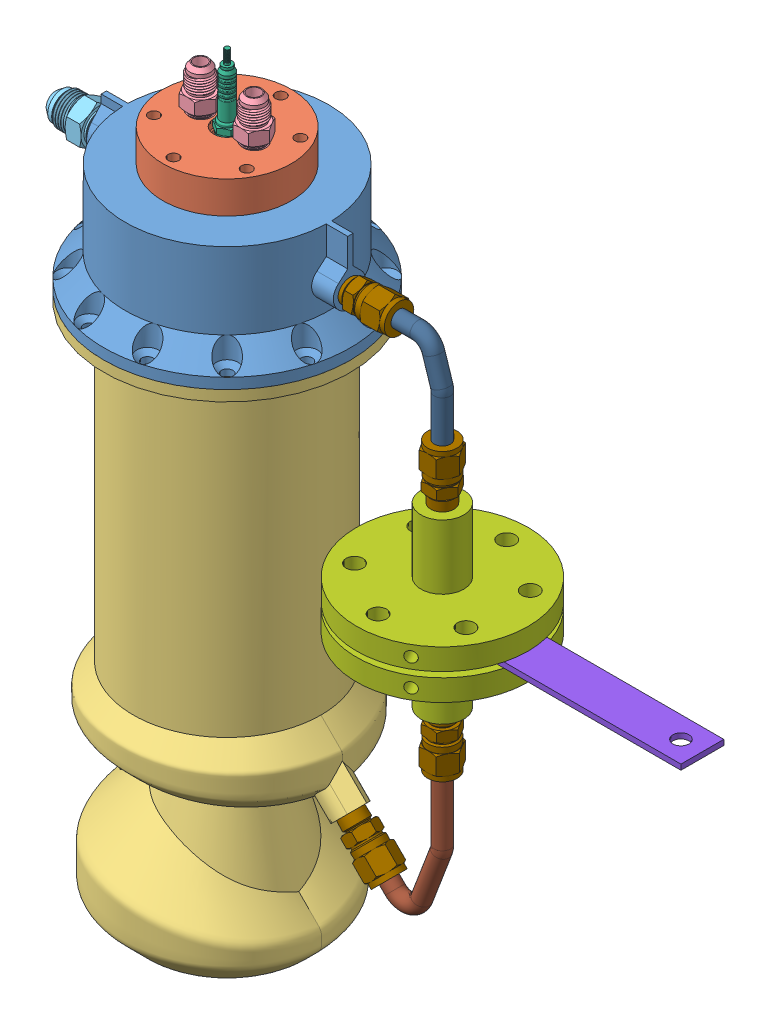
SolidWorks assembly regen additive coax swirl engine 3, configuration Default. Lengths in mm.
Overall size (382.94 487.36 146.05).
20 component instances, 11 part files, 17 mates.
Components (placement in the parent):
- addative coax swirl injector7-1: addative coax swirl injector7 [Default] at origin size (146.05 73.82 146.05)
- addative igniter 1-1: addative igniter 1 [Default] at origin size (76.2 88.9 76.2)
- slot cooling jacket 13-1: slot cooling jacket 13 [Default] at (0 5.5443 0) size (155.69 363.49 146.05)
- 5482K113_0.375AN-0.25NPT-2: 5482K113_0.375AN-0.25NPT [5482K113] at (15.875 96.9061 0) x (0 1 0) z (0 0 1) size (35.31 18.33 15.88)
- 5482K113_0.375AN-0.25NPT-3: 5482K113_0.375AN-0.25NPT [5482K113] at (-15.875 96.9061 0) x (0 1 0) z (0 0 1) size (35.31 18.33 15.88)
- 5482K114_0.5AN-0.375NPT-1: 5482K114_0.5AN-0.375NPT [5482K114] at (-82.4154 50.8 0) x (-1 0 0) z (0 0 1) size (38.48 23.83 20.64)
- 5482K114_0.5AN-0.375NPT-2: 5482K114_0.5AN-0.375NPT [5482K114] at (-66.5973 -242.1674 0) x (-0.707107 0.707107 0) z (0 0 1) size (38.48 23.83 20.64)
- SparkPlug-1: SparkPlug [Default] at (0 67.1261 0) size (15.5 63.67 13.54)
- orifice_flow_meter-1: orifice_flow_meter [Default] at (127.489 -40.2634 0) x (0 0 -1) z (1 0 0) size (138.79 104.77 223.38)
  - orifice_flow_meter_flange-1: orifice_flow_meter_flange [Default] at origin size (101.6 50.8 101.6)
  - 2206N11_Flange-Mount Flow-Control Orifice-1: 2206N11_Flange-Mount Flow-Control Orifice [2206N11] at (0 -52.3875 0) x (1 0 0) z (0 -1 0) size (53.98 180.97 3.17)
  - orifice_flow_meter_flange-2: orifice_flow_meter_flange [Default] at (0 -104.775 0) x (0.5 0 -0.866025) z (-0.866025 0 -0.5) size (101.6 50.8 101.6)
- Tube_1-regen additive coax swirl engine 3-001-1: Tube_1-regen additive coax swirl engine 3-001 [Default] at origin size (75.64 100.99 53.94)
  - straight fitting-1: straight fitting [.38 TUBE X .25 NPT] at (127.489 -47.7996 0) x (0 -1 0) z (0 0 1) size (39.88 20.16 17.46)
  - straight fitting-2: straight fitting [.38 TUBE X .25 NPT] at (61.9328 41.275 0) x (-1 0 0) z (0 0.924225 0.381849) size (39.88 20.16 17.46)
  - Tube-375X035^Tube_1-regen additive coax swirl engine 3-001-1: Tube-375X035^Tube_1-regen additive coax swirl engine 3-001 [Tube .375in OD X .035in Wall] at (127.489 -24.6856 0) x (0.707107 0 0.707107) z (0 1 0) size (38.14 38.14 70.72) (virtual)
- Tube_2-regen additive coax swirl engine 3-1: Tube_2-regen additive coax swirl engine 3 [Default] at origin size (113.38 130.09 92.49)
  - straight fitting-1: straight fitting [.38 TUBE X .25 NPT] at (67.8089 -221.0147 0) x (-0.707107 0.707107 0) z (0 0 1) size (39.88 20.16 17.46)
  - straight fitting-2: straight fitting [.38 TUBE X .25 NPT] at (127.489 -137.5023 0) x (0 1 0) z (0 0 1) size (39.88 20.16 17.46)
  - Tube-375X035^Tube_2-regen additive coax swirl engine 3-1: Tube-375X035^Tube_2-regen additive coax swirl engine 3 [Tube .375in OD X .035in Wall] at (84.153 -237.3587 0) x (0.57735 0.57735 0.57735) z (0.707107 -0.707107 0) size (77.98 58.13 63.11) (virtual)
Mates (geometry in assembly coordinates):
- Coincident1: coordinate: point of addative coax swirl injector7-1
- Coincident2: coincident aligned: cone of addative coax swirl injector7-1 through (0 26.1937 0) axis (0 -1 0); cone of addative igniter 1-1 through (0 44.45 0) axis (0 -1 0)
- Concentric2: concentric aligned: cylinder of addative coax swirl injector7-1 through (-27.4963 69.85 -15.875) axis (0 1 0) radius 2.5527; cylinder of addative igniter 1-1 through (-27.4963 88.9 -15.875) axis (0 1 0) radius 3.175
- Concentric3: concentric aligned: cylinder of addative coax swirl injector7-1 through (0 0 0) axis (0 -1 0) radius 73.025; cylinder of slot cooling jacket 13-1 through (0 -272.3803 0) axis (0 -1 0) radius 73.025
- Coincident3: coincident anti-aligned: plane of addative coax swirl injector7-1 through (-57.15 5.5443 0) normal (0 -1 0); plane of slot cooling jacket 13-1 through (-46.0375 5.5443 0) normal (0 1 0)
- Concentric4: concentric aligned: cylinder of addative coax swirl injector7-1 through (-64.4031 24.5943 -17.2568) axis (0 1 0) radius 3.3782; cylinder of slot cooling jacket 13-1 through (-64.4031 5.5443 -17.2568) axis (0 1 0) radius 3.3782
- Concentric5: concentric anti-aligned: cylinder of addative igniter 1-1 through (15.875 88.9 0) axis (0 1 0) radius 5.5626; cylinder of 5482K113_0.375AN-0.25NPT-2 through (15.875 92.075 0) axis (0 -1 0) radius 4.6517
- Distance1: distance = 3.175 mm anti-aligned: plane of 5482K113_0.375AN-0.25NPT-2 through (11.2923 92.075 -7.9375) normal (0 -1 0); plane of addative igniter 1-1 through (-38.1 88.9 0) normal (0 1 0)
- Concentric6: concentric anti-aligned: cylinder of addative igniter 1-1 through (-15.875 88.9 0) axis (0 1 0) radius 5.5626; cylinder of 5482K113_0.375AN-0.25NPT-3 through (-15.875 92.075 0) axis (0 -1 0) radius 4.6517
- Distance2: distance = 3.175 mm anti-aligned: plane of addative igniter 1-1 through (-38.1 88.9 0) normal (0 1 0); plane of 5482K113_0.375AN-0.25NPT-3 through (-20.4577 92.075 -7.9375) normal (0 -1 0)
- Concentric9: concentric anti-aligned: cylinder of slot cooling jacket 13-1 through (-59.9573 -248.8074 0) axis (-0.707107 0.707107 0) radius 7.1374; cylinder of 5482K114_0.5AN-0.375NPT-2 through (-62.2024 -246.5623 0) axis (0.707107 -0.707107 0) radius 6.36
- Distance5: distance = 3.175 mm anti-aligned: plane of 5482K114_0.5AN-0.375NPT-2 through (-66.415 -250.7749 -10.3187) normal (0.707107 -0.707107 0); plane of slot cooling jacket 13-1 through (-59.9573 -248.8074 0) normal (-0.707107 0.707107 0)
- Concentric10: concentric anti-aligned: cylinder of addative coax swirl injector7-1 through (-73.025 50.8 0) axis (-1 0 0) radius 7.1374; cylinder of 5482K114_0.5AN-0.375NPT-1 through (-76.2 50.8 0) axis (1 0 0) radius 6.36
- Distance6: distance = 3.175 mm anti-aligned: plane of 5482K114_0.5AN-0.375NPT-1 through (-76.2 44.8425 -10.3187) normal (1 0 0); cylinder of addative coax swirl injector7-1 through (0 0 0) axis (0 -1 0) radius 73.025
- Coincident8: coincident anti-aligned: plane of addative igniter 1-1 through (3.3 79.9748 0) normal (0 1 0); plane of SparkPlug-1 through (0 79.9748 -4.7405) normal (0 -1 0)
- Concentric11: concentric anti-aligned: cylinder of addative igniter 1-1 through (0 84.3548 0) axis (0 1 0) radius 3.3; cylinder of SparkPlug-1 through (0 67.1261 0) axis (0 -1 0) radius 5
- Coincident9: coincident anti-aligned: plane of orifice_flow_meter-1 through (127.489 -40.2634 0) normal (0 0 -1)
